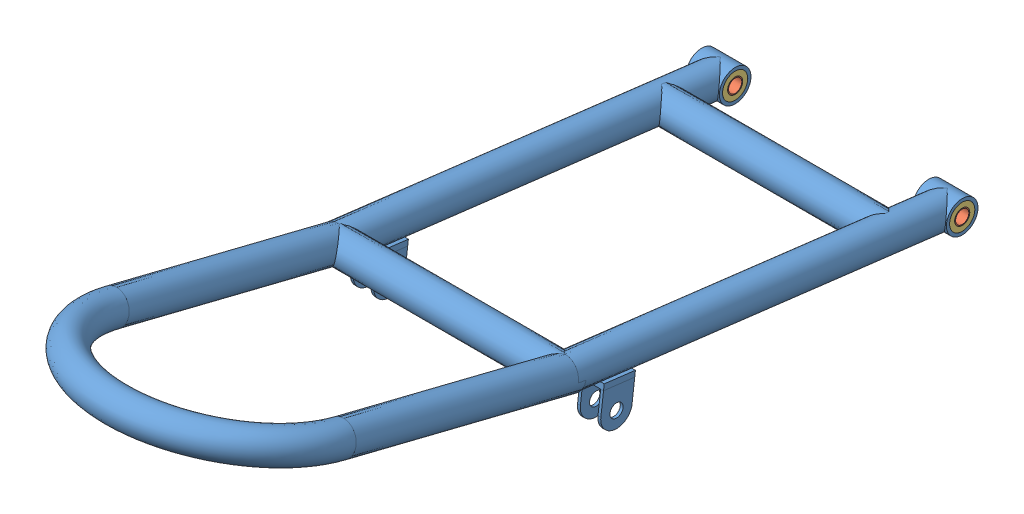
SolidWorks assembly asiento con bujes, configuration Predeterminado. Lengths in mm.
Overall size (275.4 288.82 1100.28).
5 component instances, 3 part files, 8 mates.
Components (placement in the parent):
- asiento-1: asiento [Predeterminado<Como mecanizada>] at (-9.0363 -71.7021 823.8064) size (275.4 288.82 1100.28)
- Buje pasadores-1: Buje pasadores [Predeterminado] at (93.2637 -71.7021 823.8064) size (35.4 16 16)
- Buje pasadores-2: Buje pasadores [Predeterminado] at (-146.7363 -71.7021 823.8064) size (35.4 16 16)
- Rubber bushing N-1: Rubber bushing N [Predeterminado] at (93.2637 -71.7021 823.8064) size (35.4 26.64 26.64)
- Rubber bushing N-2: Rubber bushing N [Predeterminado] at (-146.7363 -71.7021 823.8064) size (35.4 26.64 26.64)
Mates (geometry in assembly coordinates):
- Coincidente1: coincident aligned: axis of asiento-1 through (-111.3363 -71.7021 823.8064) axis (-1 0 0); axis of Buje pasadores-2 through (-111.3363 -71.7021 823.8064) axis (-1 0 0)
- Coincidente2: coincident: plane of asiento-1 through (-111.3363 -71.7021 823.8064) normal (1 0 0); plane of Buje pasadores-2 through (-111.3363 -71.7021 823.8064) normal (1 0 0)
- Coincidente3: coincident aligned: axis of asiento-1 through (128.6637 -71.7021 823.8064) axis (-1 0 0); axis of Buje pasadores-1 through (128.6637 -71.7021 823.8064) axis (-1 0 0)
- Coincidente4: coincident: plane of asiento-1 through (128.6637 -71.7021 823.8064) normal (1 0 0); plane of Buje pasadores-1 through (128.6637 -71.7021 823.8064) normal (1 0 0)
- Coincidente5: coincident aligned: axis of Buje pasadores-1 through (128.6637 -71.7021 823.8064) axis (-1 0 0); axis of Rubber bushing N-1 through (128.6637 -71.7021 823.8064) axis (-1 0 0)
- Coincidente6: coincident: plane of asiento-1 through (128.6637 -71.7021 823.8064) normal (1 0 0); plane of Rubber bushing N-1 through (128.6637 -71.7021 823.8064) normal (1 0 0)
- Coincidente7: coincident aligned: axis of asiento-1 through (-111.3363 -71.7021 823.8064) axis (-1 0 0); axis of Rubber bushing N-2 through (-111.3363 -71.7021 823.8064) axis (-1 0 0)
- Coincidente8: coincident: plane of asiento-1 through (-111.3363 -71.7021 823.8064) normal (1 0 0); plane of Rubber bushing N-2 through (-111.3363 -71.7021 823.8064) normal (1 0 0)
